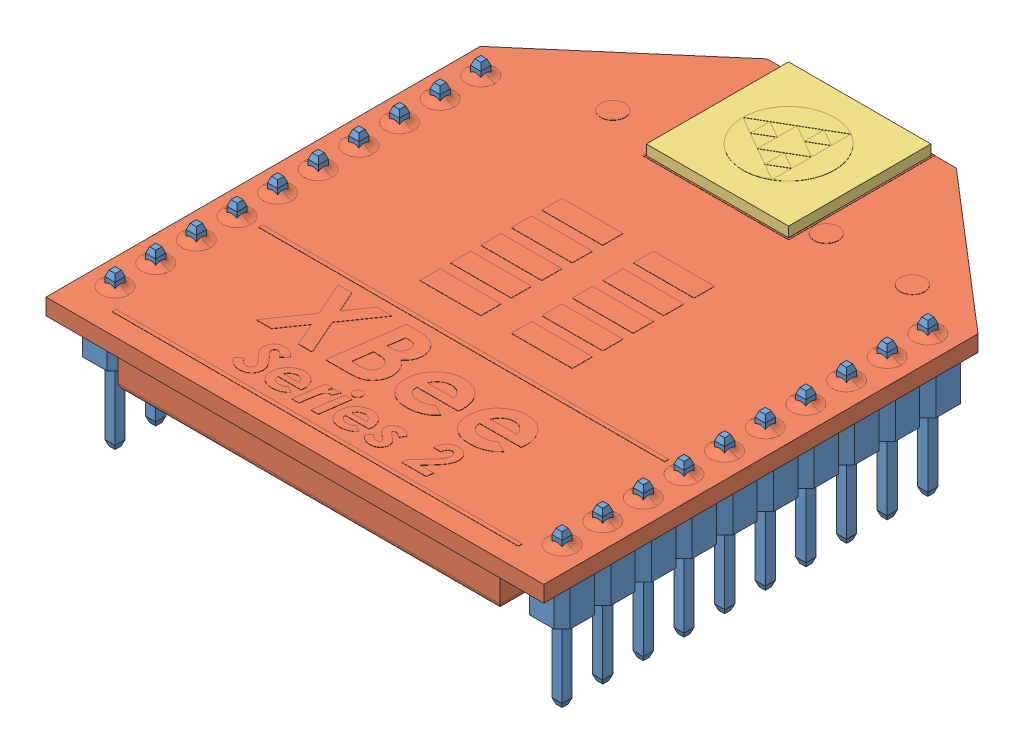
SolidWorks assembly User Library-XBee-Chip, configuration Default. Lengths in mm.
Overall size (24.5 7.5 27.9).
4 component instances, 3 part files, 0 mates.
Components (placement in the parent):
- User Library-XBee-Chip_XBee-10pin-male_1-1: User Library-XBee-Chip_XBee-10pin-male_1 [Default] at (-11 0 8.535) x (-1 0 0) z (0 0 1) size (2 7.5 20)
- User Library-XBee-Chip_XBee-Chip_1-1: User Library-XBee-Chip_XBee-Chip_1 [Default] at origin size (24.5 3.2 27.9)
- User Library-XBee-Chip_XBee-10pin-male_1-2: User Library-XBee-Chip_XBee-10pin-male_1 [Default] at (11 0 8.535) x (-1 0 0) z (0 0 1) size (2 7.5 20)
- User Library-XBee-Chip_XBee-Chip-antenna_1-1: User Library-XBee-Chip_XBee-Chip-antenna_1 [Default] at (0 0.8 -13.615) x (-1 0 0) z (0 1 0) size (7 7 0.51)
